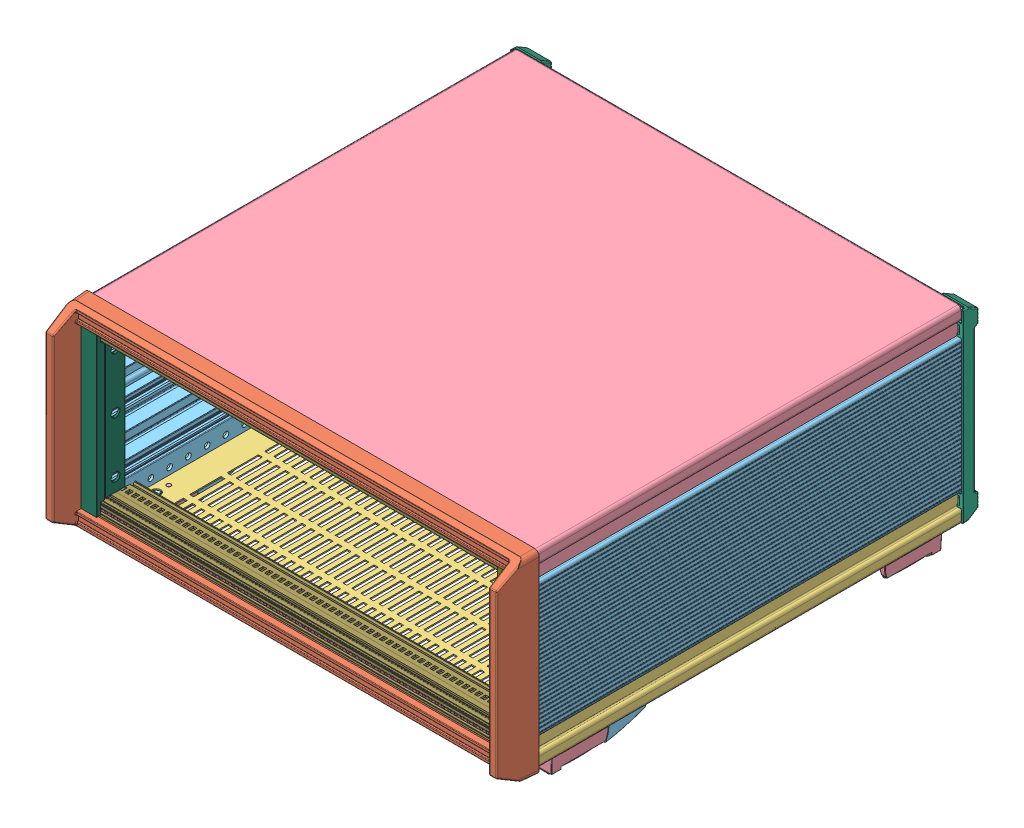
SolidWorks assembly 24576-108, configuration По умолчанию. Lengths in mm.
Overall size (363.7 168.43 385.11).
77 component instances, 23 part files, 0 mates.
Components (placement in the parent):
- propacPro-3HE-63TE-386T-1: propacPro-3HE-63TE-386T [По умолчанию] at origin size (363.7 155.5 385.11)
  - FLKOSHR-T-M-4-X16--1: FLKOSHR-T-M-4-X16- [По умолчанию] at (-168.3412 106.225 -344.3064) x (-1 0 0) z (0 0 -1) size (8.2 9.29 19.12)
  - FLKOSHR-T-M-4-X16--2: FLKOSHR-T-M-4-X16- [По умолчанию] at (-168.3412 7.275 -344.3064) x (-1 0 0) z (0 0 -1) size (8.2 9.29 19.12)
  - FLKOSHR-T-M-4-X16--3: FLKOSHR-T-M-4-X16- [По умолчанию] at (168.2788 106.225 -344.3064) x (-1 0 0) z (0 0 -1) size (8.2 9.29 19.12)
  - FLKOSHR-T-M-4-X16--4: FLKOSHR-T-M-4-X16- [По умолчанию] at (168.2788 7.275 -344.3064) x (-1 0 0) z (0 0 -1) size (8.2 9.29 19.12)
  - FLKOSHR-T-M-4-X16--5: FLKOSHR-T-M-4-X16- [По умолчанию] at (168.31 7.3 0.7325) size (8.2 9.29 19.12)
  - FLKOSHR-T-M-4-X16--6: FLKOSHR-T-M-4-X16- [По умолчанию] at (168.3057 106.25 0.7325) size (8.2 9.29 19.12)
  - FLKOSHR-T-M-4-X16--7: FLKOSHR-T-M-4-X16- [По умолчанию] at (-168.31 7.3 0.7325) size (8.2 9.29 19.12)
  - FLKOSHR-T-M-4-X16--8: FLKOSHR-T-M-4-X16- [По умолчанию] at (-168.3143 106.25 0.7325) size (8.2 9.29 19.12)
  - RAHMEN-3HE-63TE-1: RAHMEN-3HE-63TE [По умолчанию] at (0 56.775 -0.4869) size (363.7 155.5 35.01)
  - MANTEL-UN-----386T------63TE-1: MANTEL-UN-----386T------63TE [По умолчанию] at (105.4968 -18.7 -279.4965) x (1 0 0) z (0 1 0) size (358.09 344.85 32)
  - MANTEL-OB-----386T------63TE-1: MANTEL-OB-----386T------63TE [По умолчанию] at (-105.4968 132.25 -279.4965) x (-1 0 0) z (0 -1 0) size (358.09 344.85 32)
  - SEITENWAND-3HE-386T-1: SEITENWAND-3HE-386T [По умолчанию] at (-164.6599 51.8251 -183.4869) x (0 -1 0) z (0 0 -1) size (132.55 16.5 341.6)
  - SEITENWAND-3HE-386T-2: SEITENWAND-3HE-386T [По умолчанию] at (164.6599 61.7249 -183.4869) x (0 1 0) z (0 0 -1) size (132.55 16.5 341.6)
  - RUECKFUSS-3HE-vereinfacht-1: RUECKFUSS-3HE-vereinfacht [По умолчанию] at (-181.09 56.8057 -365.9751) x (0 0 1) z (-1 0 0) size (20.51 147.89 20.81)
  - RUECKFUSS-3HE-vereinfacht-2: RUECKFUSS-3HE-vereinfacht [По умолчанию] at (181.09 56.6943 -365.9751) x (0 0 1) z (1 0 0) size (20.51 147.89 20.81)
- MSAusbau-propacPro-63TE-1: MSAusbau-propacPro-63TE [По умолчанию] at (0 0 -11.9868) size (325.12 150.38 340.5)
  - MS-HI-STH063TE-----1: MS-HI-STH063TE---- [По умолчанию] at (0 113.55 -135) x (1 0 0) z (0 0 -1) size (325.12 9 27.5)
    - MS-HI-STH063TE-----1: MS-HI-STH063TE---- [По умолчанию] at origin size (325.12 9 27.5)
    - MS-HI-STH063TE----_2-1: MS-HI-STH063TE----_2 [По умолчанию] at origin size (325.12 9 27.5)
    - GS---M25-063TE-----1: GS---M25-063TE---- [По умолчанию] at origin size (324.62 5 2)
  - MS-HI-STH063TE-----2: MS-HI-STH063TE---- [По умолчанию] at (0 0 -135) x (-1 0 0) z (0 0 -1) size (325.12 9 27.5)
    - MS-HI-STH063TE-----1: MS-HI-STH063TE---- [По умолчанию] at origin size (325.12 9 27.5)
    - MS-HI-STH063TE----_2-1: MS-HI-STH063TE----_2 [По умолчанию] at origin size (325.12 9 27.5)
    - GS---M25-063TE-----1: GS---M25-063TE---- [По умолчанию] at origin size (324.62 5 2)
  - MS-HI-VTH063TE-EMC-1: MS-HI-VTH063TE-EMC [По умолчанию] at (0 113.55 -300) x (1 0 0) z (0 0 -1) size (325.12 19.02 30.5)
    - KONTAKTSTR-MS-ADBL-283.98-1: KONTAKTSTR-MS-ADBL-283.98 [По умолчанию] at origin size (285.5 16.81 12.07)
    - MS-HI-VTH063TE-----1: MS-HI-VTH063TE---- [По умолчанию] at origin size (325.12 9 30.5)
      - MS-HI-VTH063TE-----1: MS-HI-VTH063TE---- [По умолчанию] at origin size (325.12 9 30.5)
      - MS-HI-VTH063TE----_2-1: MS-HI-VTH063TE----_2 [По умолчанию] at origin size (325.12 9 30.5)
      - LS-------063TE-----1: LS-------063TE---- [По умолчанию] at origin size (324.92 5 1)
      - GS---M25-063TE-----1: GS---M25-063TE---- [По умолчанию] at origin size (324.62 5 2)
  - MS-HI-VTH063TE-EMC-2: MS-HI-VTH063TE-EMC [По умолчанию] at (0 0 -300) x (-1 0 0) z (0 0 -1) size (325.12 19.02 30.5)
    - KONTAKTSTR-MS-ADBL-283.98-1: KONTAKTSTR-MS-ADBL-283.98 [По умолчанию] at origin size (285.5 16.81 12.07)
    - MS-HI-VTH063TE-----1: MS-HI-VTH063TE---- [По умолчанию] at origin size (325.12 9 30.5)
      - MS-HI-VTH063TE-----1: MS-HI-VTH063TE---- [По умолчанию] at origin size (325.12 9 30.5)
      - MS-HI-VTH063TE----_2-1: MS-HI-VTH063TE----_2 [По умолчанию] at origin size (325.12 9 30.5)
      - LS-------063TE-----1: LS-------063TE---- [По умолчанию] at origin size (324.92 5 1)
      - GS---M25-063TE-----1: GS---M25-063TE---- [По умолчанию] at origin size (324.62 5 2)
  - MS-HI-VTH063TE-EMC-3: MS-HI-VTH063TE-EMC [По умолчанию] at (0 113.55 0) x (-1 0 0) z (0 0 1) size (325.12 19.02 30.5)
    - KONTAKTSTR-MS-ADBL-283.98-1: KONTAKTSTR-MS-ADBL-283.98 [По умолчанию] at origin size (285.5 16.81 12.07)
    - MS-HI-VTH063TE-----1: MS-HI-VTH063TE---- [По умолчанию] at origin size (325.12 9 30.5)
      - MS-HI-VTH063TE-----1: MS-HI-VTH063TE---- [По умолчанию] at origin size (325.12 9 30.5)
      - MS-HI-VTH063TE----_2-1: MS-HI-VTH063TE----_2 [По умолчанию] at origin size (325.12 9 30.5)
      - LS-------063TE-----1: LS-------063TE---- [По умолчанию] at origin size (324.92 5 1)
      - GS---M25-063TE-----1: GS---M25-063TE---- [По умолчанию] at origin size (324.62 5 2)
  - MS-HI-VTH063TE-EMC-4: MS-HI-VTH063TE-EMC [По умолчанию] at origin size (325.12 19.02 30.5)
    - KONTAKTSTR-MS-ADBL-283.98-1: KONTAKTSTR-MS-ADBL-283.98 [По умолчанию] at origin size (285.5 16.81 12.07)
    - MS-HI-VTH063TE-----1: MS-HI-VTH063TE---- [По умолчанию] at origin size (325.12 9 30.5)
      - MS-HI-VTH063TE-----1: MS-HI-VTH063TE---- [По умолчанию] at origin size (325.12 9 30.5)
      - MS-HI-VTH063TE----_2-1: MS-HI-VTH063TE----_2 [По умолчанию] at origin size (325.12 9 30.5)
      - LS-------063TE-----1: LS-------063TE---- [По умолчанию] at origin size (324.92 5 1)
      - GS---M25-063TE-----1: GS---M25-063TE---- [По умолчанию] at origin size (324.62 5 2)
  - IS-35-35-062TE-----1: IS-35-35-062TE---- [По умолчанию] at (0 113.55 -135) x (1 0 0) z (0 0 -1) size (316.88 7.8 3.8)
  - IS-35-35-062TE-----2: IS-35-35-062TE---- [По умолчанию] at (0 0 -135) x (-1 0 0) z (0 0 -1) size (316.88 7.8 3.8)
- ABDECKWINKEL-KONTAKTL-3HE-1: ABDECKWINKEL-KONTAKTL-3HE [По умолчанию] at (-156.9034 121.0001 -59.1698) x (1 0 0) z (0 1 0) size (12.5 23.5 128.45)
- ABDECKWINKEL-TRAEGERL-3HE-1: ABDECKWINKEL-TRAEGERL-3HE [По умолчанию] at (156.9035 -7.4499 -59.1698) x (-1 0 0) z (0 -1 0) size (12.5 23.5 128.45)
- 87646048-1: 87646048 [По умолчанию] at (-147.2794 1.7751 -270.3244) x (1 0 0) z (0 1 0) size (2.4 27 110)
- 87646048-2: 87646048 [По умолчанию] at (175.4405 1.7751 -270.3244) x (1 0 0) z (0 1 0) size (2.4 27 110)
- RUECKWAND 3HE 63TE-1: RUECKWAND 3HE 63TE [По умолчанию] at (-42.4303 -52.1233 -387.5969) x (-1 0 0) z (0 0 -1) size (319.7 128.4 6.2)
  - 87654102-1: 87654102 [По умолчанию] at (-185.3361 158.8483 -131.2912) x (-1 0 0) z (0 -1 0) size (3.6 5.3 100)
  - 87654117-1: 87654117 [По умолчанию] at (74.0139 158.8483 -131.2912) x (-1 0 0) z (0 -1 0) size (3.14 5.3 100)
  - RUECKWAND 3HE 63TE-1: RUECKWAND 3HE 63TE [По умолчанию] at (-14.2678 126.7846 -55.3601) size (319.7 128.4 2.5)
- 87646929-1: 87646929 [По умолчанию] at (164.04 -18.7 -315.287) x (0 0 -1) z (1 0 0) size (45.66 16.23 23.05)
  - 60842027-1: 60842027 [По умолчанию] at (-13.1638 33.8211 0) x (-1 0 0) z (0 0 1) size (7.8 7.5 17.5)
  - 87646929-1: 87646929 [По умолчанию] at (30.061 -56.7211 0) size (45.66 15.15 23.05)
- 87646929-2: 87646929 [По умолчанию] at (-164.04 -18.7 -315.287) x (0 0 -1) z (1 0 0) size (45.66 16.23 23.05)
  - 60842027-1: 60842027 [По умолчанию] at (-13.1638 33.8211 0) x (-1 0 0) z (0 0 1) size (7.8 7.5 17.5)
  - 87646929-1: 87646929 [По умолчанию] at (30.061 -56.7211 0) size (45.66 15.15 23.05)
- 87646929_2-1: 87646929_2 [По умолчанию] at (-164.04 -18.7 -30.287) x (0 0 1) z (-1 0 0) size (76.83 16.23 23.05)
  - 60842027-1: 60842027 [По умолчанию] at (-13.1638 33.8211 0) x (-1 0 0) z (0 0 1) size (7.8 7.5 17.5)
  - 87646931-1: 87646931 [По умолчанию] at (30.061 -56.7212 0) size (52.7 12.81 22.79)
  - 87646929-1: 87646929 [По умолчанию] at (30.061 -56.7211 0) size (45.66 15.15 23.05)
- 87646929_3-1: 87646929_3 [По умолчанию] at (164.04 -18.7 -30.287) x (0 0 1) z (-1 0 0) size (76.83 16.23 23.05)
  - 60842027-1: 60842027 [По умолчанию] at (-13.1638 33.8211 0) x (-1 0 0) z (0 0 1) size (7.8 7.5 17.5)
  - 87646931-1: 87646931 [По умолчанию] at (30.061 -56.7212 0) size (52.7 12.81 22.79)
  - 87646929-1: 87646929 [По умолчанию] at (30.061 -56.7211 0) size (45.66 15.15 23.05)
